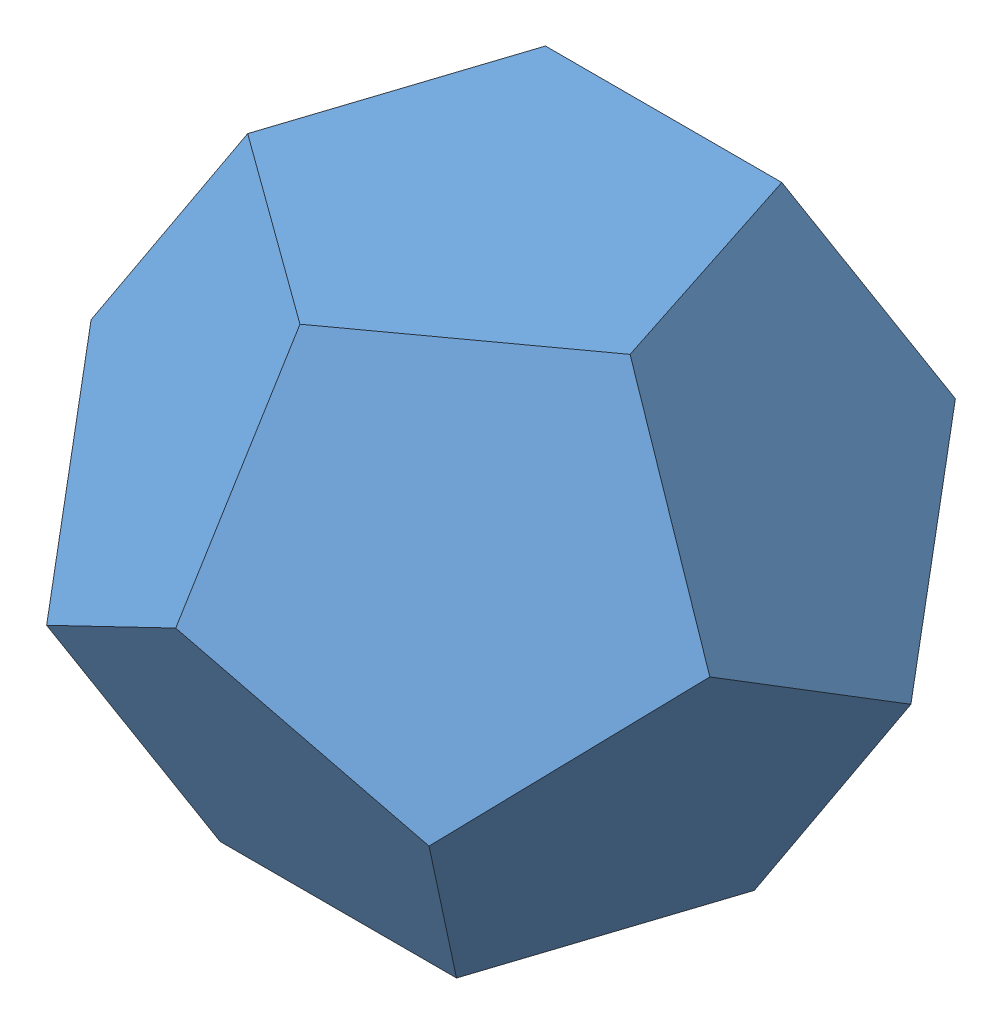
SolidWorks assembly Assem2, configuration Default. Lengths in mm.
Overall size (47.45 45.76 47.26).
3 component instances, 1 part files, 6 mates.
Components (placement in the parent):
- 4 Base Pyramid-1: 4 Base Pyramid [Default] at origin size (33.25 17.48 28.28)
- 4 Base Pyramid-2: 4 Base Pyramid [Default] at (7.4347 20.466 10.233) x (0.809017 0 -0.587785) z (-0.262866 0.894427 -0.361803) size (33.25 17.48 28.28)
- 4 Base Pyramid-3: 4 Base Pyramid [Default] at (0 20.466 -12.6487) x (0.809017 -0.525731 -0.262866) z (-0.587785 -0.723607 -0.361803) size (33.25 17.48 28.28)
Mates (geometry in assembly coordinates):
- Coincident1: coincident: plane of 4 Base Pyramid-1 through (-16.6245 17.4801 5.4016) normal (0 0.850651 -0.525731); plane of 4 Base Pyramid-3
- Coincident4: coincident aligned: line of 4 Base Pyramid-1 through (0 14.1417 0) axis (0 -0.794654 -0.607062); line of 4 Base Pyramid-3 through (0 14.1417 0) axis (0 -0.794654 -0.607062)
- Coincident5: coincident anti-aligned: plane of 4 Base Pyramid-1 through (10.2745 0 -3.3384) normal (-0.309017 0 -0.951057); plane of 4 Base Pyramid-3 through (16.6245 10.8033 -5.4016) normal (0.309017 0 0.951057)
- Coincident8: coincident: plane of 4 Base Pyramid-1 through (-10.2745 10.8033 14.1417) normal (0.309017 0.850651 0.425325); plane of 4 Base Pyramid-2 through (-38.2583 10.4508 35.1779) normal (-0.309017 -0.850651 -0.425325)
- Coincident9: coincident: plane of 4 Base Pyramid-1 through (0 17.4801 17.4801) normal (-0.5 0.850651 -0.16246); plane of 4 Base Pyramid-2 through (-10.2745 10.8033 14.1417) normal (0.5 -0.850651 0.16246)
- Coincident10: coincident: point of 4 Base Pyramid-2; point of 4 Base Pyramid-3
